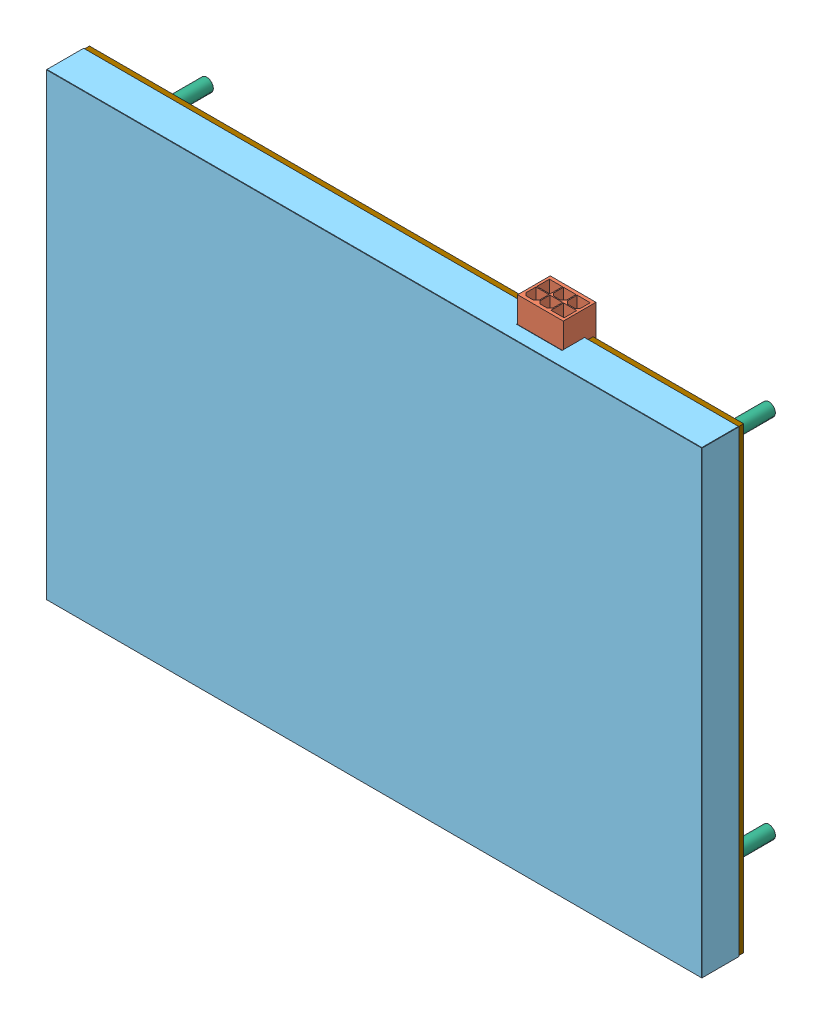
SolidWorks assembly Heated bed complete assy, configuration По умолчанию. Lengths in mm.
Overall size (200.6 148.19 34.8).
45 component instances, 9 part files, 93 mates.
Components (placement in the parent):
- Heated bed assy-1: Heated bed assy [По умолчанию] at (5.3623 -7.6782 0) size (200 147.89 14.8)
  - Heated bed-1: Heated bed [По умолчанию] at origin size (200 140 1.5)
  - MF-6 MRA-1: MF-6 MRA [По умолчанию] at (46.0967 64.8875 -5) x (0 0 -1) z (1 0 0) size (14.8 18.15 14)
- Heated Bed plate-1: Heated Bed plate [По умолчанию] at (5.3623 -7.6782 1.5) size (200 140 3)
- Heated bed frame-1: Heated bed frame [По умолчанию] at (5.3623 -7.6782 0) x (-1 0 0) z (0 0 -1) size (200 140 6)
- Heated bed cotton covering-1: Heated bed cotton covering [По умолчанию] at (5.3623 -7.6782 4.5) size (200.6 140.6 11.4)
- Countersunk Flat Head Cross Recess Screw_DIN-7: Countersunk Flat Head Cross Recess Screw_DIN [ISO 7046-1 - M4 x 30 - Z --- 30N] at (91.3623 48.3218 0) x (0 0 -1) z (0.923728 0.383049 0) size (30 8.4 8.4)
- Countersunk Flat Head Cross Recess Screw_DIN-8: Countersunk Flat Head Cross Recess Screw_DIN [ISO 7046-1 - M4 x 30 - Z --- 30N] at (-80.6377 -63.6782 0) x (0 0 -1) z (0.919758 0.392486 0) size (30 8.4 8.4)
- Countersunk Flat Head Cross Recess Screw_DIN-9: Countersunk Flat Head Cross Recess Screw_DIN [ISO 7046-1 - M4 x 30 - Z --- 30N] at (-80.6377 48.3218 0) x (0 0 -1) z (0.923728 0.383049 0) size (30 8.4 8.4)
- Countersunk Flat Head Cross Recess Screw_DIN-10: Countersunk Flat Head Cross Recess Screw_DIN [ISO 7046-1 - M4 x 30 - Z --- 30N] at (91.3623 -63.6782 0) x (0 0 -1) z (0.923728 0.383049 0) size (30 8.4 8.4)
- Plain Washer 6903 Type AB_DIN-5: Plain Washer 6903 Type AB_DIN [DIN 6903-A4] at (-80.6377 48.3218 -6) x (0 0 -1) z (1 0 0) size (1 10 10)
- Plain Washer 6903 Type AB_DIN-6: Plain Washer 6903 Type AB_DIN [DIN 6903-A4] at (91.3623 48.3218 -6) x (0 0 -1) z (1 0 0) size (1 10 10)
- Plain Washer 6903 Type AB_DIN-7: Plain Washer 6903 Type AB_DIN [DIN 6903-A4] at (91.3623 -63.6782 -6) x (0 0 -1) z (1 0 0) size (1 10 10)
- Plain Washer 6903 Type AB_DIN-8: Plain Washer 6903 Type AB_DIN [DIN 6903-A4] at (-80.6377 -63.6782 -6) x (0 0 -1) z (1 0 0) size (1 10 10)
- Hex Nut Style 1 GradeAB_DIN-1: Hex Nut Style 1 GradeAB_DIN [Hexagon Nut ISO 4032 - M4 - D - N] at (-80.6377 -63.6782 -7) x (0.024954 -0.999689 0) z (0 0 1) size (7 8.08 3.2)
- Hex Nut Style 1 GradeAB_DIN-2: Hex Nut Style 1 GradeAB_DIN [Hexagon Nut ISO 4032 - M4 - D - N] at (91.3623 -63.6782 -10.2) x (0.923728 0.383049 0) z (0 0 -1) size (7 8.08 3.2)
- Hex Nut Style 1 GradeAB_DIN-3: Hex Nut Style 1 GradeAB_DIN [Hexagon Nut ISO 4032 - M4 - D - N] at (91.3623 48.3218 -10.2) x (0.923728 0.383049 0) z (0 0 -1) size (7 8.08 3.2)
- Hex Nut Style 1 GradeAB_DIN-4: Hex Nut Style 1 GradeAB_DIN [Hexagon Nut ISO 4032 - M4 - D - N] at (-80.6377 48.3218 -10.2) x (0.923728 0.383049 0) z (0 0 -1) size (7 8.08 3.2)
- Heated bed textolite insulator-1: Heated bed textolite insulator [По умолчанию] at (5.3623 -7.6782 -6.6) x (-1 0 0) z (0 0 -1) size (200.2 140.2 1.5)
- Countersunk Flat Head Cross Recess Screw_DIN-11: Countersunk Flat Head Cross Recess Screw_DIN [ISO 7046-1 - M3 x 16 - Z --- 16N] at (-87.6377 55.3218 4.5) x (0 0 -1) z (1 0 0) size (16 5.5 5.5)
- Countersunk Flat Head Cross Recess Screw_DIN-12: Countersunk Flat Head Cross Recess Screw_DIN [ISO 7046-1 - M3 x 16 - Z --- 16N] at (98.3623 55.3218 4.5) x (0 0 -1) z (1 0 0) size (16 5.5 5.5)
- Countersunk Flat Head Cross Recess Screw_DIN-13: Countersunk Flat Head Cross Recess Screw_DIN [ISO 7046-1 - M3 x 16 - Z --- 16N] at (98.3623 -70.6782 4.5) x (0 0 -1) z (1 0 0) size (16 5.5 5.5)
- Countersunk Flat Head Cross Recess Screw_DIN-14: Countersunk Flat Head Cross Recess Screw_DIN [ISO 7046-1 - M3 x 16 - Z --- 16N] at (5.3623 -37.6782 4.5) x (0 0 -1) z (1 0 0) size (16 5.5 5.5)
- Countersunk Flat Head Cross Recess Screw_DIN-15: Countersunk Flat Head Cross Recess Screw_DIN [ISO 7046-1 - M3 x 16 - Z --- 16N] at (5.3623 22.3218 4.5) x (0 0 -1) z (1 0 0) size (16 5.5 5.5)
- Countersunk Flat Head Cross Recess Screw_DIN-16: Countersunk Flat Head Cross Recess Screw_DIN [ISO 7046-1 - M3 x 16 - Z --- 16N] at (-87.6377 -70.6782 4.5) x (0 0 -1) z (1 0 0) size (16 5.5 5.5)
- Plain Washer 6903 Type AB_DIN-13: Plain Washer 6903 Type AB_DIN [DIN 6903-A3] at (98.3623 55.3218 1.5) x (0 0 -1) z (1 0 0) size (1 8 8)
- Plain Washer 6903 Type AB_DIN-14: Plain Washer 6903 Type AB_DIN [DIN 6903-A3] at (98.3623 -70.6782 1.5) x (0 0 -1) z (1 0 0) size (1 8 8)
- Plain Washer 6903 Type AB_DIN-15: Plain Washer 6903 Type AB_DIN [DIN 6903-A3] at (-87.6377 -70.6782 1.5) x (0 0 -1) z (1 0 0) size (1 8 8)
- Plain Washer 6903 Type AB_DIN-16: Plain Washer 6903 Type AB_DIN [DIN 6903-A3] at (-87.6377 55.3218 1.5) x (0 0 -1) z (1 0 0) size (1 8 8)
- Hex Nut Style 1 GradeAB_DIN-9: Hex Nut Style 1 GradeAB_DIN [Hexagon Nut ISO 4032 - M3 - D - N] at (-87.6377 55.3218 -1.9) x (-0.98787 0.155286 0) z (0 0 -1) size (5.5 6.35 2.4)
- Hex Nut Style 1 GradeAB_DIN-10: Hex Nut Style 1 GradeAB_DIN [Hexagon Nut ISO 4032 - M3 - D - N] at (98.3623 55.3218 -1.9) x (0.923728 0.383049 0) z (0 0 -1) size (5.5 6.35 2.4)
- Hex Nut Style 1 GradeAB_DIN-11: Hex Nut Style 1 GradeAB_DIN [Hexagon Nut ISO 4032 - M3 - D - N] at (98.3623 -70.6782 -1.9) x (0.923728 0.383049 0) z (0 0 -1) size (5.5 6.35 2.4)
- Hex Nut Style 1 GradeAB_DIN-12: Hex Nut Style 1 GradeAB_DIN [Hexagon Nut ISO 4032 - M3 - D - N] at (-87.6377 -70.6782 -1.9) x (0.923728 0.383049 0) z (0 0 -1) size (5.5 6.35 2.4)
- Plain Washer 6903 Type AB_DIN-17: Plain Washer 6903 Type AB_DIN [DIN 6903-A3] at (98.3623 55.3218 -8.1) x (0 0 -1) z (1 0 0) size (1 8 8)
- Plain Washer 6903 Type AB_DIN-18: Plain Washer 6903 Type AB_DIN [DIN 6903-A3] at (-87.6377 55.3218 -8.1) x (0 0 -1) z (1 0 0) size (1 8 8)
- Plain Washer 6903 Type AB_DIN-19: Plain Washer 6903 Type AB_DIN [DIN 6903-A3] at (-87.6377 -70.6782 -8.1) x (0 0 -1) z (1 0 0) size (1 8 8)
- Plain Washer 6903 Type AB_DIN-20: Plain Washer 6903 Type AB_DIN [DIN 6903-A3] at (98.3623 -70.6782 -8.1) x (0 0 -1) z (1 0 0) size (1 8 8)
- Plain Washer 6903 Type AB_DIN-21: Plain Washer 6903 Type AB_DIN [DIN 6903-A3] at (5.3623 -37.6782 -8.1) x (0 0 -1) z (1 0 0) size (1 8 8)
- Plain Washer 6903 Type AB_DIN-22: Plain Washer 6903 Type AB_DIN [DIN 6903-A3] at (5.3623 22.3218 -8.1) x (0 0 -1) z (1 0 0) size (1 8 8)
- Hex Nut Style 1 GradeAB_DIN-13: Hex Nut Style 1 GradeAB_DIN [Hexagon Nut ISO 4032 - M3 - D - N] at (-87.6377 -70.6782 -11.5) x (-0.55763 -0.830089 0) z (0 0 -1) size (5.5 6.35 2.4)
- Hex Nut Style 1 GradeAB_DIN-14: Hex Nut Style 1 GradeAB_DIN [Hexagon Nut ISO 4032 - M3 - D - N] at (-87.6377 55.3218 -11.5) x (0.923728 0.383049 0) z (0 0 -1) size (5.5 6.35 2.4)
- Hex Nut Style 1 GradeAB_DIN-15: Hex Nut Style 1 GradeAB_DIN [Hexagon Nut ISO 4032 - M3 - D - N] at (5.3623 22.3218 -11.5) x (0.923728 0.383049 0) z (0 0 -1) size (5.5 6.35 2.4)
- Hex Nut Style 1 GradeAB_DIN-16: Hex Nut Style 1 GradeAB_DIN [Hexagon Nut ISO 4032 - M3 - D - N] at (5.3623 -37.6782 -11.5) x (0.923728 0.383049 0) z (0 0 -1) size (5.5 6.35 2.4)
- Hex Nut Style 1 GradeAB_DIN-17: Hex Nut Style 1 GradeAB_DIN [Hexagon Nut ISO 4032 - M3 - D - N] at (98.3623 55.3218 -11.5) x (0.923728 0.383049 0) z (0 0 -1) size (5.5 6.35 2.4)
- Hex Nut Style 1 GradeAB_DIN-18: Hex Nut Style 1 GradeAB_DIN [Hexagon Nut ISO 4032 - M3 - D - N] at (98.3623 -70.6782 -11.5) x (0.923728 0.383049 0) z (0 0 -1) size (5.5 6.35 2.4)
Mates (geometry in assembly coordinates):
- На месте2: in place: plane of Heated bed assy-1/Heated bed-1 through (-94.6377 62.3218 1.5) normal (0 0 1); plane of ? through (0 0 1.5) normal (0 0 1); moOrthogonalPlaneRef_w of Heated bed assy-1/Heated bed-1 through (-94.6377 62.3218 1.5) normal (0 0 1); plane of ? through (0 0 1.5) normal (0 1 0); plane of Heated bed assy-1/Heated bed-1 through (-94.6377 62.3218 1.5) normal (0 0 1); plane of ? through (0 0 1.5) normal (1 0 0); plane of Heated bed assy-1/Heated bed-1 through (-94.6377 62.3218 1.5) normal (0 0 1); unknown of Heated Bed plate-1
- Совпадение4: coincident aligned: plane of Heated bed assy-1/Heated bed-1; plane of Heated Bed plate-1
- Совпадение5: coincident aligned: moOrthogonalPlaneRef_w of Heated bed assy-1/Heated bed-1 through (5.3623 -7.6782 1.5) normal (0 1 0); plane of Heated Bed plate-1 through (5.3623 -7.6782 1.5) normal (0 1 0)
- Совпадение6: coincident anti-aligned: moOrthogonalPlaneRef_w of Heated bed assy-1/Heated bed-1 through (5.3623 -7.6782 1.5) normal (-1 0 0); plane of Heated Bed plate-1 through (5.3623 -7.6782 1.5) normal (1 0 0)
- На месте3: in place: plane of Heated bed assy-1/Heated bed-1 through (-94.6377 62.3218 0) normal (0 0 -1); plane of ? through (0 0 0) normal (0 0 -1); plane of Heated bed assy-1/Heated bed-1 through (-94.6377 62.3218 0) normal (0 0 -1); line of ? through (-55 0 0) axis (0 0 1); plane of Heated bed assy-1/Heated bed-1 through (-94.6377 62.3218 0) normal (0 0 -1); plane of ? through (0 0 0) normal (-1 0 0); plane of Heated bed assy-1/Heated bed-1 through (-94.6377 62.3218 0) normal (0 0 -1); unknown of Heated bed frame-1
- Совпадение19: coincident aligned: plane of Heated bed assy-1/Heated bed-1; plane of Heated bed frame-1
- Совпадение20: coincident aligned: moOrthogonalPlaneRef_w of Heated bed assy-1/Heated bed-1 through (5.3623 -7.6782 0) normal (0 1 0); plane of Heated bed frame-1
- Совпадение21: coincident anti-aligned: moOrthogonalPlaneRef_w of Heated bed assy-1/Heated bed-1 through (5.3623 -7.6782 0) normal (1 0 0); plane of Heated bed frame-1 through (5.3623 -7.6782 0) normal (-1 0 0)
- На месте4: in place: plane of Heated Bed plate-1 through (5.3623 -197.7091 4.5) normal (0 0 1); plane of ? through (0 0 4.5) normal (0 0 1); plane of Heated Bed plate-1 through (5.3623 -197.7091 4.5) normal (0 0 1); plane of ? through (0 0 4.5) normal (0 1 0); plane of Heated Bed plate-1 through (5.3623 -197.7091 4.5) normal (0 0 1); plane of ? through (0 0 4.5) normal (1 0 0); plane of Heated Bed plate-1 through (5.3623 -197.7091 4.5) normal (0 0 1); unknown of Heated bed cotton covering-1
- Совпадение22: coincident aligned: plane of Heated Bed plate-1; plane of Heated bed cotton covering-1
- Совпадение23: coincident aligned: moOrthogonalPlaneRef_w of Heated Bed plate-1 through (5.3623 -7.6782 4.5) normal (0 1 0); plane of Heated bed cotton covering-1 through (5.3623 -7.6782 4.5) normal (0 1 0)
- Совпадение24: coincident anti-aligned: moOrthogonalPlaneRef_w of Heated Bed plate-1 through (5.3623 -7.6782 4.5) normal (-1 0 0); plane of Heated bed cotton covering-1 through (5.3623 -7.6782 4.5) normal (1 0 0)
- Совпадение25: coincident aligned: plane of Countersunk Flat Head Cross Recess Screw_DIN-8 through (-80.6377 -63.6782 0) normal (0 0 1); plane of Countersunk Flat Head Cross Recess Screw_DIN-10 through (91.3623 -63.6782 0) normal (0 0 1)
- Совпадение26: coincident aligned: plane of Countersunk Flat Head Cross Recess Screw_DIN-9 through (-80.6377 48.3218 0) normal (0 0 1); plane of Countersunk Flat Head Cross Recess Screw_DIN-10 through (91.3623 -63.6782 0) normal (0 0 1)
- Совпадение27: coincident aligned: plane of Countersunk Flat Head Cross Recess Screw_DIN-7 through (91.3623 48.3218 0) normal (0 0 1); plane of Countersunk Flat Head Cross Recess Screw_DIN-9 through (-80.6377 48.3218 0) normal (0 0 1)
- Совпадение28: coincident aligned: plane of Heated bed frame-1 through (5.3623 -197.7091 0) normal (0 0 1); plane of Countersunk Flat Head Cross Recess Screw_DIN-7 through (91.3623 48.3218 0) normal (0 0 1)
- Концентричный13: concentric aligned: cylinder of Heated bed frame-1 through (91.3623 48.3218 -6) axis (0 0 1) radius 2; cylinder of Countersunk Flat Head Cross Recess Screw_DIN-7 through (91.3623 48.3218 6.35) axis (0 0 1) radius 2
- Концентричный14: concentric aligned: cylinder of Heated bed frame-1 through (-80.6377 48.3218 -6) axis (0 0 1) radius 2; cylinder of Countersunk Flat Head Cross Recess Screw_DIN-9 through (-80.6377 48.3218 6.35) axis (0 0 1) radius 2
- Концентричный15: concentric aligned: cylinder of Heated bed frame-1 through (91.3623 -63.6782 -6) axis (0 0 1) radius 2; cylinder of Countersunk Flat Head Cross Recess Screw_DIN-10 through (91.3623 -63.6782 6.35) axis (0 0 1) radius 2
- Концентричный16: concentric aligned: cylinder of Heated bed frame-1 through (-80.6377 -63.6782 -6) axis (0 0 1) radius 2; cylinder of Countersunk Flat Head Cross Recess Screw_DIN-8 through (-80.6377 -63.6782 6.35) axis (0 0 1) radius 2
- Концентричный21: concentric aligned: cylinder of Countersunk Flat Head Cross Recess Screw_DIN-9 through (-80.6377 48.3218 6.35) axis (0 0 1) radius 2; cylinder of Plain Washer 6903 Type AB_DIN-5 through (-80.6377 48.3218 -7) axis (0 0 1) radius 2
- Совпадение33: coincident anti-aligned: plane of Heated bed frame-1 through (5.3623 -197.7091 -6) normal (0 0 -1); plane of Plain Washer 6903 Type AB_DIN-5 through (-80.6377 48.3218 -6) normal (0 0 1)
- Концентричный22: concentric aligned: cylinder of Countersunk Flat Head Cross Recess Screw_DIN-7 through (91.3623 48.3218 6.35) axis (0 0 1) radius 2; cylinder of Plain Washer 6903 Type AB_DIN-6 through (91.3623 48.3218 -7) axis (0 0 1) radius 2
- Совпадение34: coincident anti-aligned: plane of Heated bed frame-1 through (5.3623 -197.7091 -6) normal (0 0 -1); plane of Plain Washer 6903 Type AB_DIN-6 through (91.3623 48.3218 -6) normal (0 0 1)
- Концентричный23: concentric aligned: cylinder of Countersunk Flat Head Cross Recess Screw_DIN-10 through (91.3623 -63.6782 6.35) axis (0 0 1) radius 2; cylinder of Plain Washer 6903 Type AB_DIN-7 through (91.3623 -63.6782 -7) axis (0 0 1) radius 2
- Совпадение35: coincident anti-aligned: plane of Heated bed frame-1 through (5.3623 -197.7091 -6) normal (0 0 -1); plane of Plain Washer 6903 Type AB_DIN-7 through (91.3623 -63.6782 -6) normal (0 0 1)
- Концентричный24: concentric aligned: cylinder of Countersunk Flat Head Cross Recess Screw_DIN-8 through (-80.6377 -63.6782 6.35) axis (0 0 1) radius 2; cylinder of Plain Washer 6903 Type AB_DIN-8 through (-80.6377 -63.6782 -7) axis (0 0 1) radius 2
- Совпадение36: coincident anti-aligned: plane of Heated bed frame-1 through (5.3623 -197.7091 -6) normal (0 0 -1); plane of Plain Washer 6903 Type AB_DIN-8 through (-80.6377 -63.6782 -6) normal (0 0 1)
- Концентричный26: concentric aligned: cylinder of Countersunk Flat Head Cross Recess Screw_DIN-8 through (-80.6377 -63.6782 6.35) axis (0 0 1) radius 2; cylinder of Hex Nut Style 1 GradeAB_DIN-1 through (-80.6377 -63.6782 -32.0375) axis (0 0 1) radius 2
- Концентричный251: concentric aligned: cylinder of Countersunk Flat Head Cross Recess Screw_DIN-8 through (-80.6377 -63.6782 6.35) axis (0 0 1) radius 2; cylinder of Hex Nut Style 1 GradeAB_DIN-1 through (-80.6377 -63.6782 -32.0375) axis (0 0 1) radius 2
- Концентричный27: concentric anti-aligned: cylinder of Countersunk Flat Head Cross Recess Screw_DIN-10 through (91.3623 -63.6782 6.35) axis (0 0 1) radius 2; cylinder of Hex Nut Style 1 GradeAB_DIN-2 through (91.3623 -63.6782 14.8375) axis (0 0 -1) radius 2
- Совпадение37: coincident anti-aligned: plane of Plain Washer 6903 Type AB_DIN-7 through (91.3623 -63.6782 -7) normal (0 0 -1); plane of Hex Nut Style 1 GradeAB_DIN-2 through (84.8962 -66.3596 -7) normal (0 0 1)
- Концентричный28: concentric anti-aligned: cylinder of Countersunk Flat Head Cross Recess Screw_DIN-7 through (91.3623 48.3218 6.35) axis (0 0 1) radius 2; cylinder of Hex Nut Style 1 GradeAB_DIN-3 through (91.3623 48.3218 14.8375) axis (0 0 -1) radius 2
- Совпадение38: coincident anti-aligned: plane of Plain Washer 6903 Type AB_DIN-6 through (91.3623 48.3218 -7) normal (0 0 -1); plane of Hex Nut Style 1 GradeAB_DIN-3 through (84.8962 45.6404 -7) normal (0 0 1)
- Концентричный29: concentric anti-aligned: cylinder of Countersunk Flat Head Cross Recess Screw_DIN-9 through (-80.6377 48.3218 6.35) axis (0 0 1) radius 2; cylinder of Hex Nut Style 1 GradeAB_DIN-4 through (-80.6377 48.3218 14.8375) axis (0 0 -1) radius 2
- Совпадение39: coincident anti-aligned: plane of Plain Washer 6903 Type AB_DIN-5 through (-80.6377 48.3218 -7) normal (0 0 -1); plane of Hex Nut Style 1 GradeAB_DIN-4 through (-87.1038 45.6404 -7) normal (0 0 1)
- Совпадение40: coincident anti-aligned: plane of Plain Washer 6903 Type AB_DIN-8 through (-80.6377 -63.6782 -7) normal (0 0 -1); plane of Hex Nut Style 1 GradeAB_DIN-1 through (-80.8124 -56.6804 -7) normal (0 0 1)
- На месте5: in place: plane of Heated bed cotton covering-1 through (105.6623 -77.9782 -6.6) normal (0 0 -1); plane of ? through (0 0 -6.6) normal (0 0 -1); plane of Heated bed cotton covering-1 through (105.6623 -77.9782 -6.6) normal (0 0 -1); unknown of ?; plane of Heated bed cotton covering-1 through (105.6623 -77.9782 -6.6) normal (0 0 -1); plane of ? through (0 0 -6.6) normal (-1 0 0); plane of Heated bed cotton covering-1 through (105.6623 -77.9782 -6.6) normal (0 0 -1); unknown of Heated bed textolite insulator-1
- Совпадение41: coincident aligned: plane of Heated bed cotton covering-1; plane of Heated bed textolite insulator-1
- Совпадение42: coincident aligned: moOrthogonalPlaneRef_w of Heated bed cotton covering-1 through (5.3623 -7.6782 -6.6) normal (0 1 0); plane of Heated bed textolite insulator-1
- Совпадение43: coincident anti-aligned: moOrthogonalPlaneRef_w of Heated bed cotton covering-1 through (5.3623 -7.6782 -6.6) normal (1 0 0); plane of Heated bed textolite insulator-1 through (5.3623 -7.6782 -6.6) normal (-1 0 0)
- Совпадение52: coincident aligned: plane of Countersunk Flat Head Cross Recess Screw_DIN-11 through (-87.6377 55.3218 4.5) normal (0 0 1); plane of Countersunk Flat Head Cross Recess Screw_DIN-12 through (98.3623 55.3218 4.5) normal (0 0 1)
- Совпадение53: coincident aligned: plane of Countersunk Flat Head Cross Recess Screw_DIN-11 through (-87.6377 55.3218 4.5) normal (0 0 1); plane of Countersunk Flat Head Cross Recess Screw_DIN-13 through (98.3623 -70.6782 4.5) normal (0 0 1)
- Совпадение54: coincident aligned: plane of Countersunk Flat Head Cross Recess Screw_DIN-13 through (98.3623 -70.6782 4.5) normal (0 0 1); plane of Countersunk Flat Head Cross Recess Screw_DIN-15 through (5.3623 22.3218 4.5) normal (0 0 1)
- Совпадение55: coincident aligned: plane of Countersunk Flat Head Cross Recess Screw_DIN-15 through (5.3623 22.3218 4.5) normal (0 0 1); plane of Countersunk Flat Head Cross Recess Screw_DIN-16 through (-87.6377 -70.6782 4.5) normal (0 0 1)
- Совпадение56: coincident aligned: plane of Countersunk Flat Head Cross Recess Screw_DIN-14 through (5.3623 -37.6782 4.5) normal (0 0 1); plane of Countersunk Flat Head Cross Recess Screw_DIN-16 through (-87.6377 -70.6782 4.5) normal (0 0 1)
- Совпадение57: coincident aligned: plane of Heated Bed plate-1 through (5.3623 -197.7091 4.5) normal (0 0 1); plane of Countersunk Flat Head Cross Recess Screw_DIN-14 through (5.3623 -37.6782 4.5) normal (0 0 1)
- Концентричный38: concentric anti-aligned: cylinder of Heated Bed plate-1 through (98.3623 55.3218 4.5) axis (0 0 -1) radius 1.5; cylinder of Countersunk Flat Head Cross Recess Screw_DIN-12 through (98.3623 55.3218 10.85) axis (0 0 1) radius 1.5
- Концентричный39: concentric anti-aligned: cylinder of Heated Bed plate-1 through (98.3623 -70.6782 4.5) axis (0 0 -1) radius 1.5; cylinder of Countersunk Flat Head Cross Recess Screw_DIN-13 through (98.3623 -70.6782 10.85) axis (0 0 1) radius 1.5
- Концентричный40: concentric anti-aligned: cylinder of Heated Bed plate-1 through (5.3623 22.3218 4.5) axis (0 0 -1) radius 1.5; cylinder of Countersunk Flat Head Cross Recess Screw_DIN-15 through (5.3623 22.3218 10.85) axis (0 0 1) radius 1.5
- Концентричный41: concentric anti-aligned: cylinder of Heated Bed plate-1 through (5.3623 -37.6782 4.5) axis (0 0 -1) radius 1.5; cylinder of Countersunk Flat Head Cross Recess Screw_DIN-14 through (5.3623 -37.6782 10.85) axis (0 0 1) radius 1.5
- Концентричный42: concentric anti-aligned: cylinder of Heated Bed plate-1 through (-87.6377 -70.6782 4.5) axis (0 0 -1) radius 1.5; cylinder of Countersunk Flat Head Cross Recess Screw_DIN-16 through (-87.6377 -70.6782 10.85) axis (0 0 1) radius 1.5
- Концентричный43: concentric anti-aligned: cylinder of Heated Bed plate-1 through (-87.6377 55.3218 4.5) axis (0 0 -1) radius 1.5; cylinder of Countersunk Flat Head Cross Recess Screw_DIN-11 through (-87.6377 55.3218 10.85) axis (0 0 1) radius 1.5
- Концентричный44: concentric aligned: cylinder of Countersunk Flat Head Cross Recess Screw_DIN-12 through (98.3623 55.3218 10.85) axis (0 0 1) radius 1.5; cylinder of Plain Washer 6903 Type AB_DIN-13 through (98.3623 55.3218 0.5) axis (0 0 1) radius 1.5
- Совпадение58: coincident anti-aligned: plane of Heated Bed plate-1 through (5.3623 -197.7091 1.5) normal (0 0 -1); plane of Plain Washer 6903 Type AB_DIN-13 through (98.3623 55.3218 1.5) normal (0 0 1)
- Концентричный45: concentric aligned: cylinder of Countersunk Flat Head Cross Recess Screw_DIN-13 through (98.3623 -70.6782 10.85) axis (0 0 1) radius 1.5; cylinder of Plain Washer 6903 Type AB_DIN-14 through (98.3623 -70.6782 0.5) axis (0 0 1) radius 1.5
- Совпадение59: coincident anti-aligned: plane of Heated Bed plate-1 through (5.3623 -197.7091 1.5) normal (0 0 -1); plane of Plain Washer 6903 Type AB_DIN-14 through (98.3623 -70.6782 1.5) normal (0 0 1)
- Концентричный46: concentric aligned: cylinder of Countersunk Flat Head Cross Recess Screw_DIN-16 through (-87.6377 -70.6782 10.85) axis (0 0 1) radius 1.5; cylinder of Plain Washer 6903 Type AB_DIN-15 through (-87.6377 -70.6782 0.5) axis (0 0 1) radius 1.5
- Совпадение60: coincident anti-aligned: plane of Heated Bed plate-1 through (5.3623 -197.7091 1.5) normal (0 0 -1); plane of Plain Washer 6903 Type AB_DIN-15 through (-87.6377 -70.6782 1.5) normal (0 0 1)
- Концентричный47: concentric aligned: cylinder of Countersunk Flat Head Cross Recess Screw_DIN-11 through (-87.6377 55.3218 10.85) axis (0 0 1) radius 1.5; cylinder of Plain Washer 6903 Type AB_DIN-16 through (-87.6377 55.3218 0.5) axis (0 0 1) radius 1.5
- Совпадение61: coincident anti-aligned: plane of Heated Bed plate-1 through (5.3623 -197.7091 1.5) normal (0 0 -1); plane of Plain Washer 6903 Type AB_DIN-16 through (-87.6377 55.3218 1.5) normal (0 0 1)
- Концентричный48: concentric anti-aligned: cylinder of Countersunk Flat Head Cross Recess Screw_DIN-11 through (-87.6377 55.3218 10.85) axis (0 0 1) radius 1.5; cylinder of Hex Nut Style 1 GradeAB_DIN-9 through (-87.6377 55.3218 23.1375) axis (0 0 -1) radius 1.5
- Совпадение62: coincident anti-aligned: plane of Plain Washer 6903 Type AB_DIN-16 through (-87.6377 55.3218 0.5) normal (0 0 -1); plane of Hex Nut Style 1 GradeAB_DIN-9 through (-87.1446 58.4587 0.5) normal (0 0 1)
- Концентричный49: concentric anti-aligned: cylinder of Countersunk Flat Head Cross Recess Screw_DIN-12 through (98.3623 55.3218 10.85) axis (0 0 1) radius 1.5; cylinder of Hex Nut Style 1 GradeAB_DIN-10 through (98.3623 55.3218 23.1375) axis (0 0 -1) radius 1.5
- Совпадение63: coincident anti-aligned: plane of Plain Washer 6903 Type AB_DIN-13 through (98.3623 55.3218 0.5) normal (0 0 -1); plane of Hex Nut Style 1 GradeAB_DIN-10 through (99.5786 52.3886 0.5) normal (0 0 1)
- Концентричный50: concentric anti-aligned: cylinder of Plain Washer 6903 Type AB_DIN-14 through (98.3623 -70.6782 0.5) axis (0 0 1) radius 4; cylinder of Hex Nut Style 1 GradeAB_DIN-11 through (98.3623 -70.6782 23.1375) axis (0 0 -1) radius 1.5
- Совпадение64: coincident anti-aligned: plane of Plain Washer 6903 Type AB_DIN-14 through (98.3623 -70.6782 0.5) normal (0 0 -1); plane of Hex Nut Style 1 GradeAB_DIN-11 through (99.5786 -73.6114 0.5) normal (0 0 1)
- Концентричный51: concentric anti-aligned: cylinder of Countersunk Flat Head Cross Recess Screw_DIN-16 through (-87.6377 -70.6782 10.85) axis (0 0 1) radius 1.5; cylinder of Hex Nut Style 1 GradeAB_DIN-12 through (-87.6377 -70.6782 23.1375) axis (0 0 -1) radius 1.5
- Совпадение65: coincident anti-aligned: plane of Plain Washer 6903 Type AB_DIN-15 through (-87.6377 -70.6782 0.5) normal (0 0 -1); plane of Hex Nut Style 1 GradeAB_DIN-12 through (-86.4214 -73.6114 0.5) normal (0 0 1)
- Концентричный52: concentric aligned: cylinder of Countersunk Flat Head Cross Recess Screw_DIN-12 through (98.3623 55.3218 10.85) axis (0 0 1) radius 1.5; cylinder of Plain Washer 6903 Type AB_DIN-17 through (98.3623 55.3218 -9.1) axis (0 0 1) radius 1.5
- Совпадение66: coincident anti-aligned: plane of Heated bed textolite insulator-1 through (5.4623 -197.8257 -8.1) normal (0 0 -1); plane of Plain Washer 6903 Type AB_DIN-17 through (98.3623 55.3218 -8.1) normal (0 0 1)
- Концентричный53: concentric aligned: cylinder of Countersunk Flat Head Cross Recess Screw_DIN-11 through (-87.6377 55.3218 10.85) axis (0 0 1) radius 1.5; cylinder of Plain Washer 6903 Type AB_DIN-18 through (-87.6377 55.3218 -9.1) axis (0 0 1) radius 1.5
- Совпадение67: coincident anti-aligned: plane of Heated bed textolite insulator-1 through (5.4623 -197.8257 -8.1) normal (0 0 -1); plane of Plain Washer 6903 Type AB_DIN-18 through (-87.6377 55.3218 -8.1) normal (0 0 1)
- Концентричный54: concentric aligned: cylinder of Countersunk Flat Head Cross Recess Screw_DIN-16 through (-87.6377 -70.6782 10.85) axis (0 0 1) radius 1.5; cylinder of Plain Washer 6903 Type AB_DIN-19 through (-87.6377 -70.6782 -9.1) axis (0 0 1) radius 1.5
- Совпадение68: coincident anti-aligned: plane of Heated bed textolite insulator-1 through (5.4623 -197.8257 -8.1) normal (0 0 -1); plane of Plain Washer 6903 Type AB_DIN-19 through (-87.6377 -70.6782 -8.1) normal (0 0 1)
- Концентричный55: concentric aligned: cylinder of Countersunk Flat Head Cross Recess Screw_DIN-13 through (98.3623 -70.6782 10.85) axis (0 0 1) radius 1.5; cylinder of Plain Washer 6903 Type AB_DIN-20 through (98.3623 -70.6782 -9.1) axis (0 0 1) radius 1.5
- Совпадение69: coincident anti-aligned: plane of Heated bed textolite insulator-1 through (5.4623 -197.8257 -8.1) normal (0 0 -1); plane of Plain Washer 6903 Type AB_DIN-20 through (98.3623 -70.6782 -8.1) normal (0 0 1)
- Концентричный56: concentric aligned: cylinder of Countersunk Flat Head Cross Recess Screw_DIN-14 through (5.3623 -37.6782 10.85) axis (0 0 1) radius 1.5; cylinder of Plain Washer 6903 Type AB_DIN-21 through (5.3623 -37.6782 -9.1) axis (0 0 1) radius 1.5
- Совпадение70: coincident anti-aligned: plane of Heated bed textolite insulator-1 through (5.4623 -197.8257 -8.1) normal (0 0 -1); plane of Plain Washer 6903 Type AB_DIN-21 through (5.3623 -37.6782 -8.1) normal (0 0 1)
- Концентричный57: concentric aligned: cylinder of Countersunk Flat Head Cross Recess Screw_DIN-15 through (5.3623 22.3218 10.85) axis (0 0 1) radius 1.5; cylinder of Plain Washer 6903 Type AB_DIN-22 through (5.3623 22.3218 -9.1) axis (0 0 1) radius 1.5
- Совпадение71: coincident anti-aligned: plane of Heated bed textolite insulator-1 through (5.4623 -197.8257 -8.1) normal (0 0 -1); plane of Plain Washer 6903 Type AB_DIN-22 through (5.3623 22.3218 -8.1) normal (0 0 1)
- Концентричный58: concentric anti-aligned: cylinder of Countersunk Flat Head Cross Recess Screw_DIN-16 through (-87.6377 -70.6782 10.85) axis (0 0 1) radius 1.5; cylinder of Hex Nut Style 1 GradeAB_DIN-13 through (-87.6377 -70.6782 13.5375) axis (0 0 -1) radius 1.5
- Совпадение72: coincident anti-aligned: plane of Plain Washer 6903 Type AB_DIN-19 through (-87.6377 -70.6782 -9.1) normal (0 0 -1); plane of Hex Nut Style 1 GradeAB_DIN-13 through (-90.2736 -68.9075 -9.1) normal (0 0 1)
- Концентричный59: concentric anti-aligned: cylinder of Countersunk Flat Head Cross Recess Screw_DIN-11 through (-87.6377 55.3218 10.85) axis (0 0 1) radius 1.5; cylinder of Hex Nut Style 1 GradeAB_DIN-14 through (-87.6377 55.3218 13.5375) axis (0 0 -1) radius 1.5
- Совпадение73: coincident anti-aligned: plane of Plain Washer 6903 Type AB_DIN-18 through (-87.6377 55.3218 -9.1) normal (0 0 -1); plane of Hex Nut Style 1 GradeAB_DIN-14 through (-86.4214 52.3886 -9.1) normal (0 0 1)
- Концентричный60: concentric anti-aligned: cylinder of Countersunk Flat Head Cross Recess Screw_DIN-15 through (5.3623 22.3218 10.85) axis (0 0 1) radius 1.5; cylinder of Hex Nut Style 1 GradeAB_DIN-15 through (5.3623 22.3218 13.5375) axis (0 0 -1) radius 1.5
- Совпадение74: coincident anti-aligned: plane of Plain Washer 6903 Type AB_DIN-22 through (5.3623 22.3218 -9.1) normal (0 0 -1); plane of Hex Nut Style 1 GradeAB_DIN-15 through (6.5786 19.3886 -9.1) normal (0 0 1)
- Концентричный61: concentric anti-aligned: cylinder of Countersunk Flat Head Cross Recess Screw_DIN-14 through (5.3623 -37.6782 10.85) axis (0 0 1) radius 1.5; cylinder of Hex Nut Style 1 GradeAB_DIN-16 through (5.3623 -37.6782 13.5375) axis (0 0 -1) radius 1.5
- Совпадение75: coincident anti-aligned: plane of Plain Washer 6903 Type AB_DIN-21 through (5.3623 -37.6782 -9.1) normal (0 0 -1); plane of Hex Nut Style 1 GradeAB_DIN-16 through (6.5786 -40.6114 -9.1) normal (0 0 1)
- Концентричный62: concentric anti-aligned: cylinder of Countersunk Flat Head Cross Recess Screw_DIN-12 through (98.3623 55.3218 10.85) axis (0 0 1) radius 1.5; cylinder of Hex Nut Style 1 GradeAB_DIN-17 through (98.3623 55.3218 13.5375) axis (0 0 -1) radius 1.5
- Совпадение76: coincident anti-aligned: plane of Plain Washer 6903 Type AB_DIN-17 through (98.3623 55.3218 -9.1) normal (0 0 -1); plane of Hex Nut Style 1 GradeAB_DIN-17 through (99.5786 52.3886 -9.1) normal (0 0 1)
- Концентричный63: concentric anti-aligned: cylinder of Countersunk Flat Head Cross Recess Screw_DIN-13 through (98.3623 -70.6782 10.85) axis (0 0 1) radius 1.5; cylinder of Hex Nut Style 1 GradeAB_DIN-18 through (98.3623 -70.6782 13.5375) axis (0 0 -1) radius 1.5
- Совпадение77: coincident anti-aligned: plane of Plain Washer 6903 Type AB_DIN-20 through (98.3623 -70.6782 -9.1) normal (0 0 -1); plane of Hex Nut Style 1 GradeAB_DIN-18 through (99.5786 -73.6114 -9.1) normal (0 0 1)
